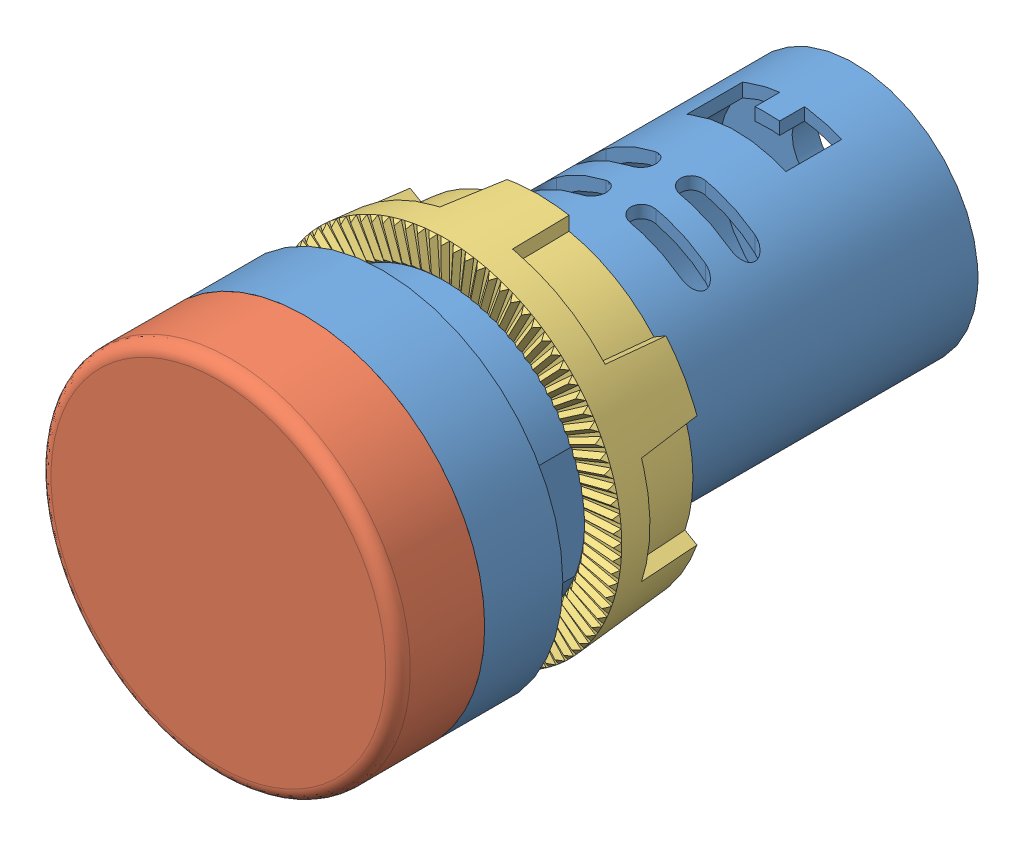
SolidWorks assembly Green panel light assembly, configuration Default. Lengths in mm.
Overall size (29 29 51.3).
4 component instances, 4 part files, 6 mates.
Components (placement in the parent):
- light panel-3: light panel [Default] at (34.5891 -25.4136 -10.6015) size (29 29 44.3)
- light green-2: light green [Default] at (34.5891 -25.4136 40.6985) x (1 0 0) z (0 1 0) size (29 11 29)
- light nut-2: light nut [Default] at (34.5891 -25.4136 22.3985) x (1 0 0) z (0 1 0) size (28.5 7.84 28.5)
- light reflector-2: light reflector [Default] at (34.5891 -25.4136 38.3985) x (1 0 0) z (0 1 0) size (23.7 10 23.7)
Mates (geometry in assembly coordinates):
- Concentric4: concentric anti-aligned: cylinder of light panel-3 through (34.5891 -25.4136 33.6985) axis (0 0 -1) radius 14; cylinder of light reflector-2 through (34.5891 -25.4136 37.3985) axis (0 0 1) radius 11.85
- Coincident4: coincident anti-aligned: plane of light panel-3 through (34.5891 -25.4136 28.3985) normal (0 0 1); circle of light reflector-2
- Coincident5: coincident anti-aligned: plane of light panel-3 through (34.5891 -25.4136 33.6985) normal (0 0 1); plane of light green-2 through (34.5891 -25.4136 33.6985) normal (0 0 -1)
- Concentric5: concentric anti-aligned: circle of light green-2; cylinder of light reflector-2 through (34.5891 -25.4136 37.3985) axis (0 0 1) radius 11.85
- Concentric6: concentric: cylinder of light panel-3 through (34.5891 -25.4136 27.3985) axis (0 0 -1) radius 10; cylinder of light nut-2 through (34.5891 -25.4136 22.3985) axis (0 0 -1) radius 11.25
- Distance2: distance = 5 mm anti-aligned: plane of light nut-2 through (34.5891 -25.4136 22.3985) normal (0 0 1); plane of light panel-3 through (34.5891 -25.4136 27.3985) normal (0 0 -1)
